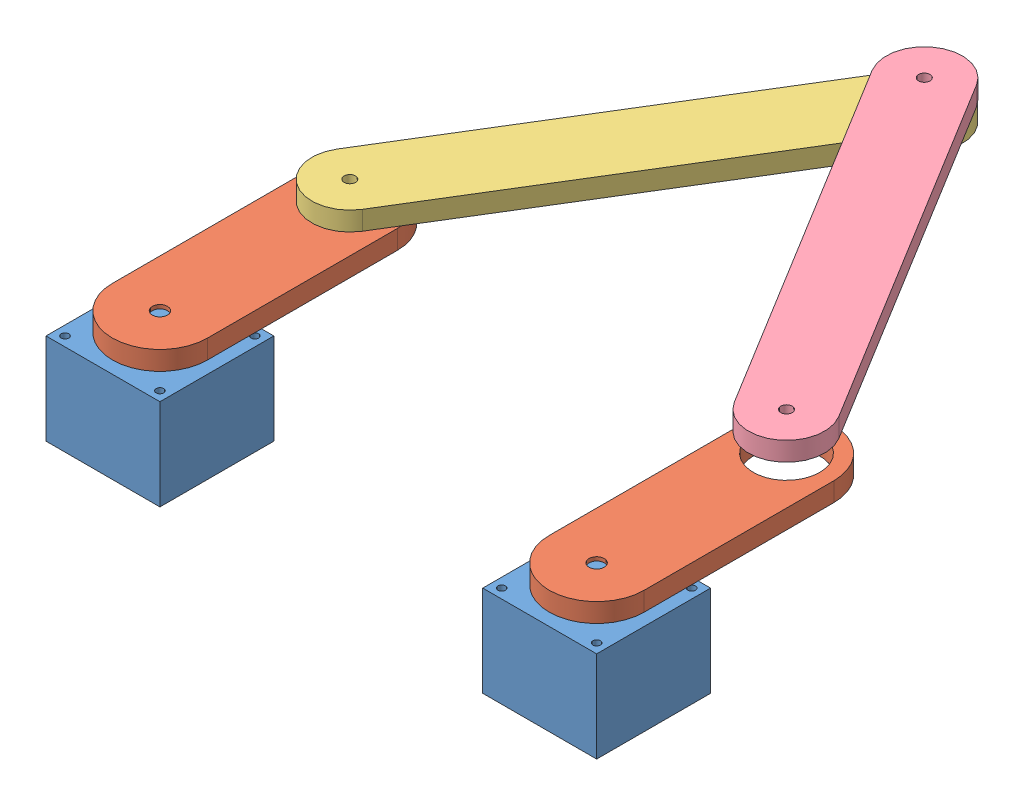
SolidWorks assembly Final Assembly, configuration Default. Lengths in mm.
Overall size (290 110 345.05).
6 component instances, 4 part files, 15 mates.
Components (placement in the parent):
- Stepper Motor-1: Stepper Motor [Default] at (-115 0 0) size (60 57.5 60)
- Stepper Motor-2: Stepper Motor [Default] at (115 0 0) size (60 57.5 60)
- Link A-1: Link A [Default] at (-115 49.5 0) x (0 0 -1) z (1 0 0) size (150 10 50)
- Link B M-F-1: Link B M-F [Default] at (0 59.5 -287.55) x (-0.522727 0 0.8525) z (-0.8525 0 -0.522727) size (260 10 40)
- Link B M-M-1: Link B M-M [Default] at (0 69.5 -287.55) x (0.522727 0 0.8525) z (-0.8525 0 0.522727) size (260 10 40)
- Link A-3: Link A [Default] at (115 49.5 0) x (0 0 -1) z (1 0 0) size (150 10 50)
Mates (geometry in assembly coordinates):
- Coincident1: coincident anti-aligned: plane of Stepper Motor-1 through (-115 0 0) normal (0 -1 0)
- Coincident2: coincident aligned: plane of Stepper Motor-1 through (-115 0 0) normal (1 0 0)
- Coincident3: coincident aligned: plane of Stepper Motor-1 through (-115 0 0) normal (0 0 1)
- Coincident4: coincident aligned: plane of Stepper Motor-2 through (115 0 0) normal (1 0 0)
- Coincident5: coincident anti-aligned: plane of Stepper Motor-2 through (115 0 0) normal (0 -1 0)
- Coincident6: coincident aligned: plane of Stepper Motor-2 through (115 0 0) normal (0 0 1)
- Coincident9: coincident anti-aligned: plane of Stepper Motor-1 through (-97 49.5 0) normal (0 1 0); plane of Link A-1 through (-115 49.5 0) normal (0 -1 0)
- Concentric1: concentric anti-aligned: cylinder of Stepper Motor-1 through (-115 57.5 0) axis (0 1 0) radius 4; cylinder of Link A-1 through (-115 59.5 0) axis (0 -1 0) radius 4
- Coincident10: coincident anti-aligned: plane of Stepper Motor-2 through (133 49.5 0) normal (0 1 0); plane of Link A-3 through (115 49.5 0) normal (0 -1 0)
- Concentric2: concentric anti-aligned: cylinder of Stepper Motor-2 through (115 57.5 0) axis (0 1 0) radius 4; cylinder of Link A-3 through (115 59.5 0) axis (0 -1 0) radius 4
- Coincident13: coincident anti-aligned: plane of Link A-1 through (-115 59.5 0) normal (0 1 0); plane of Link B M-F-1 through (-115 59.5 -100) normal (0 -1 0)
- Coincident15: coincident anti-aligned: plane of Link B M-F-1 through (-115 69.5 -100) normal (0 1 0); plane of Link B M-M-1 through (115 69.5 -100) normal (0 -1 0)
- Concentric9: concentric aligned: cylinder of Link A-1 through (-115 59.5 -100) axis (0 -1 0) radius 17.5; cylinder of Link B M-F-1 through (-115 69.5 -100) axis (0 -1 0) radius 3
- Concentric10: concentric aligned: cylinder of Link B M-F-1 through (0 69.5 -287.55) axis (0 -1 0) radius 13; cylinder of Link B M-M-1 through (0 79.5 -287.55) axis (0 -1 0) radius 3
- Concentric11: concentric aligned: cylinder of Link B M-M-1 through (115 79.5 -100) axis (0 -1 0) radius 3; cylinder of Link A-3 through (115 59.5 -100) axis (0 -1 0) radius 17.5
